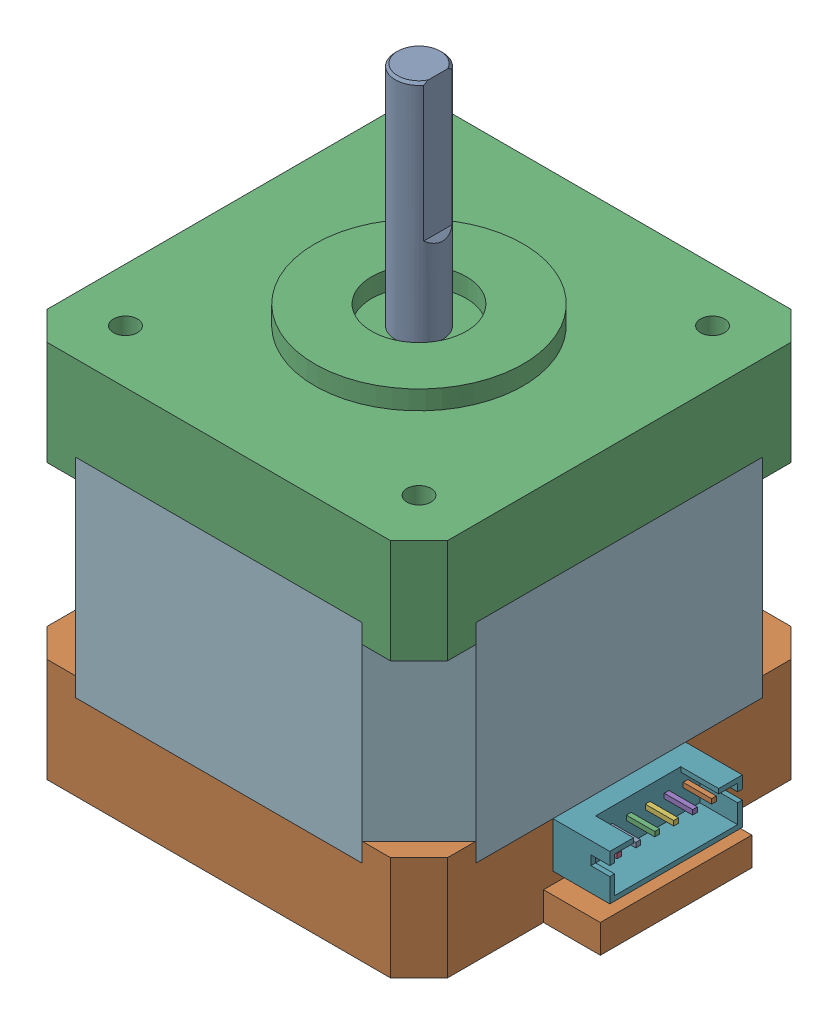
SolidWorks assembly Nema 17 40mm.step, configuration Default. Lengths in mm.
Overall size (48.3 64 42.3).
15 component instances, 7 part files, 0 mates.
Components (placement in the parent):
- JST 2.0 PH - 6 Pin.step-1: JST 2.0 PH - 6 Pin.step [Default] at (21.15 9 -7) x (0 0 1) z (0 1 0) size (14 9.4 4.8)
  - Pin.step-1: Pin.step [Default] at origin size (10.5 8.4 0.5)
  - JST 2.0 PH - 6 Pin-0.step-1: JST 2.0 PH - 6 Pin-0.step [Default] at origin size (14 6 4.8)
- M3 x 15mm.step-1: M3 x 15mm.step [Default] at (15.5 18 15.5) x (1 0 0) z (0 1 0) size (5.5 5.5 18)
  - M3 x 15mm-1.step-1: M3 x 15mm-1.step [Default] at origin size (5.5 5.5 18)
- M3 x 15mm.step-2: M3 x 15mm.step [Default] at (15.5 18 -15.5) x (1 0 0) z (0 1 0) size (5.5 5.5 18)
  - M3 x 15mm-1.step-1: M3 x 15mm-1.step [Default] at origin size (5.5 5.5 18)
- M3 x 15mm.step-3: M3 x 15mm.step [Default] at (-15.5 18 15.5) x (1 0 0) z (0 1 0) size (5.5 5.5 18)
  - M3 x 15mm-1.step-1: M3 x 15mm-1.step [Default] at origin size (5.5 5.5 18)
- M3 x 15mm.step-4: M3 x 15mm.step [Default] at (-15.5 18 -15.5) x (1 0 0) z (0 1 0) size (5.5 5.5 18)
  - M3 x 15mm-1.step-1: M3 x 15mm-1.step [Default] at origin size (5.5 5.5 18)
- Mid.step-1: Mid.step [Default] at origin size (42.3 22 42.3)
- Shaft.step-1: Shaft.step [Default] at origin size (5 24 5)
- Nema 17 40mm-2.step-1: Nema 17 40mm-2.step [Default] at origin size (48.3 11 42.3)
- Nema 17 40mm-3.step-1: Nema 17 40mm-3.step [Default] at origin size (42.3 13 42.3)
